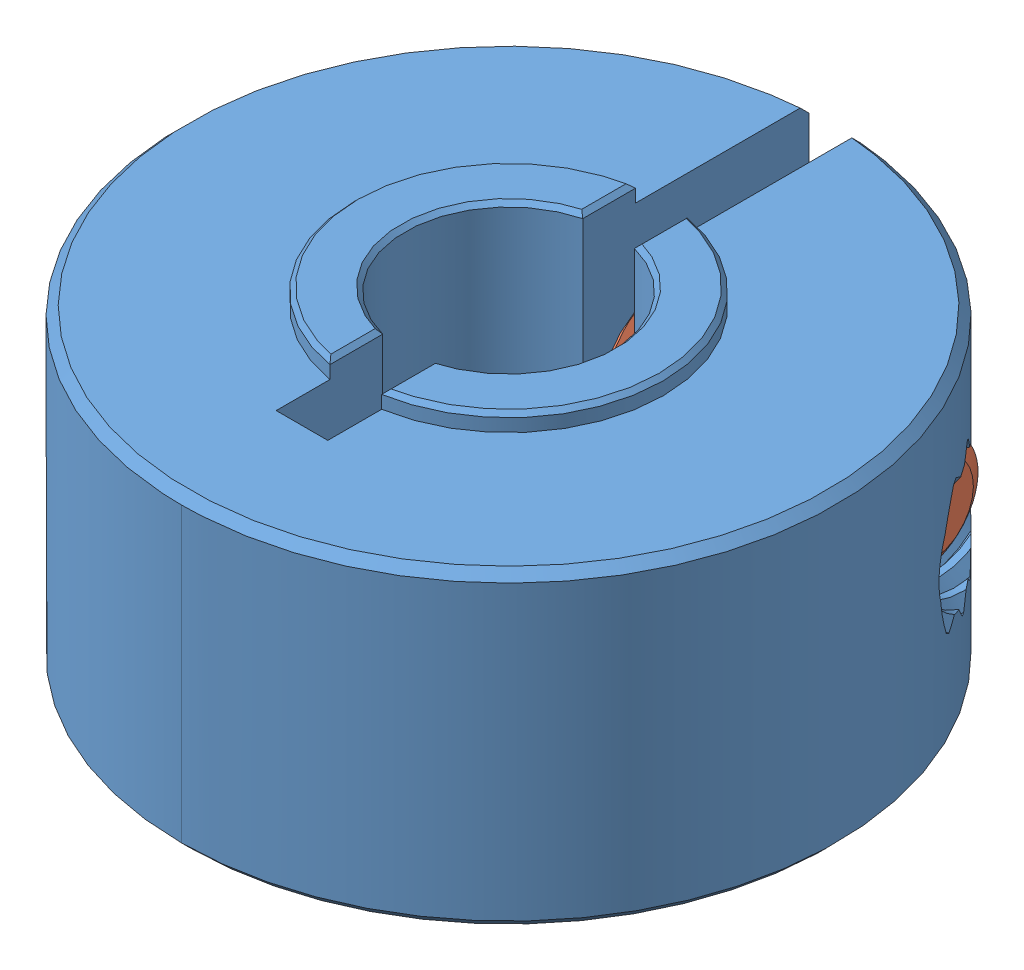
SolidWorks assembly 2910-0919-0006, configuration Default. Lengths in mm.
Overall size (19 9.89 19.83).
3 component instances, 2 part files, 0 mates.
Components (placement in the parent):
- 2910-0919-0006 assembly.STEP-1: 2910-0919-0006 assembly.STEP [Default] at origin size (19 9.89 19.83)
  - 2910-0919-0006.STEP-1: 2910-0919-0006.STEP [Default] at (-31.0565 -0.5204 16.7268) size (19 9.5 18.97)
  - 2800-0004-0010_90128A207.STEP-1: 2800-0004-0010_90128A207.STEP [Default] at (-24.2865 -0.5204 11.2868) x (0 -0.807243 -0.59022) z (1 0 0) size (7 7 14.01)
